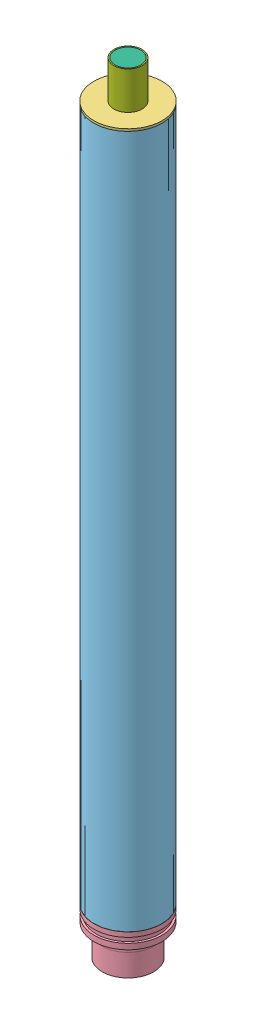
SolidWorks assembly N2850_Reload_Asm, configuration Default. Lengths in mm.
Overall size (129.5 1052.3 129.5).
16 component instances, 7 part files, 30 mates.
Components (placement in the parent):
- N2850P_Grain-1: N2850P_Grain [Default] at (67.2787 -348.6977 28.0701) size (85.47 152.4 85.47)
- N2850P_Grain-2: N2850P_Grain [Default] at (67.2787 -656.7997 28.0701) x (0.90713 0 0.42085) z (-0.42085 0 0.90713) size (85.47 152.4 85.47)
- N2850P_Grain-3: N2850P_Grain [Default] at (67.2787 -1117.3017 28.0701) x (0.920776 0 0.390092) z (-0.390092 0 0.920776) size (85.47 152.4 85.47)
- N2850P_Grain-4: N2850P_Grain [Default] at (67.2787 -809.1997 28.0701) x (0.999333 0 -0.03651) z (0.03651 0 0.999333) size (85.47 152.4 85.47)
- N2850P_Grain-5: N2850P_Grain [Default] at (67.2787 -502.7487 28.0701) x (-0.989532 0 0.144312) z (-0.144312 0 -0.989532) size (85.47 152.4 85.47)
- N2850P_Grain_O_Ring-1: N2850P_Grain_O_Ring [Default] at (67.2787 -503.5742 28.0701) x (0.875027 0 -0.484075) z (0.484075 0 0.875027) size (85.47 1.65 85.47)
- N2850P_Grain_O_Ring-2: N2850P_Grain_O_Ring [Default] at (67.2787 -657.6252 28.0701) x (0.935457 0 0.353441) z (-0.353441 0 0.935457) size (85.47 1.65 85.47)
- N2850P_Grain_O_Ring-3: N2850P_Grain_O_Ring [Default] at (67.2787 -349.5232 28.0701) x (0.895254 0 -0.445557) z (0.445557 0 0.895254) size (85.47 1.65 85.47)
- N2850P_Grain_O_Ring-4: N2850P_Grain_O_Ring [Default] at (67.2787 -964.0762 28.0701) size (85.47 1.65 85.47)
- N2850P_Grain_O_Ring-5: N2850P_Grain_O_Ring [Default] at (67.2787 -810.0252 28.0701) x (0.989289 0 -0.145969) z (0.145969 0 0.989289) size (85.47 1.65 85.47)
- N2850P_Grain-6: N2850P_Grain [Default] at (67.2787 -963.2507 28.0701) x (0.981998 0 0.188893) z (-0.188893 0 0.981998) size (85.47 152.4 85.47)
- N2850P_Forward_Seal_Disc-1: N2850P_Forward_Seal_Disc [Default] at (67.2787 -186.6203 28.0701) size (92.15 6.17 92.15)
- N2850P_Nozel-1: N2850P_Nozel [Default] at (67.2787 -1175.2142 28.0701) x (-1 0 0) z (0 0 1) size (91.69 70.82 91.69)
- N2850P_Reload_Liner-1: N2850P_Reload_Liner [Default] at (67.2787 -189.6429 28.0701) x (-0.742612 0 0.669722) z (0.669722 0 0.742612) size (91.69 936.62 91.69)
- N2850P_Smoke_Grain-1: N2850P_Smoke_Grain [Default] at (67.2787 -135.8711 28.0701) x (1 0 0) z (0 -1 0) size (34.8 34.8 50.75)
- N2850P_Smoke_Grain_Liner-1: N2850P_Smoke_Grain_Liner [Default] at (67.2787 -135.8203 28.0701) x (1 0 0) z (0 -1 0) size (38.1 38.1 50.8)
Mates (geometry in assembly coordinates):
- Coincident2: coincident aligned: axis of N2850P_Nozel-1 through (67.2787 -1188.1169 28.0701) axis (0 1 0); axis of N2850P_Reload_Liner-1 through (67.2787 -1126.2679 28.0701) axis (0 1 0)
- Coincident3: coincident anti-aligned: plane of N2850P_Nozel-1 through (110.2047 -1126.2679 28.0701) normal (0 1 0); plane of N2850P_Reload_Liner-1 through (67.2787 -1126.2679 28.0701) normal (0 -1 0)
- Coincident4: coincident aligned: axis of N2850P_Smoke_Grain-1 through (67.2787 -186.6203 28.0701) axis (0 1 0); axis of N2850P_Smoke_Grain_Liner-1 through (67.2787 -186.6203 28.0701) axis (0 1 0)
- Coincident5: coincident aligned: plane of N2850P_Smoke_Grain-1 through (67.2787 -186.6203 28.0701) normal (0 -1 0); plane of N2850P_Smoke_Grain_Liner-1 through (67.2787 -186.6203 28.0701) normal (0 -1 0)
- Coincident6: coincident anti-aligned: plane of N2850P_Forward_Seal_Disc-1 through (57.7537 -186.6203 28.0701) normal (0 1 0); plane of N2850P_Smoke_Grain-1 through (67.2787 -186.6203 28.0701) normal (0 -1 0)
- Coincident7: coincident aligned: axis of N2850P_Forward_Seal_Disc-1 through (67.2787 -192.7925 28.0701) axis (0 1 0); axis of N2850P_Smoke_Grain-1 through (67.2787 -186.6203 28.0701) axis (0 1 0)
- Coincident8: coincident aligned: axis of N2850P_Forward_Seal_Disc-1 through (67.2787 -192.7925 28.0701) axis (0 1 0); axis of N2850P_Reload_Liner-1 through (67.2787 -1126.2679 28.0701) axis (0 1 0)
- Coincident9: coincident aligned: axis of N2850P_Grain-4 through (67.2787 -656.7997 28.0701) axis (0 -1 0); axis of N2850P_Grain_O_Ring-2 through (67.2787 -633.4481 28.0701) axis (0 -1 0)
- Coincident10: coincident aligned: axis of N2850P_Grain-2 through (67.2787 -504.3997 28.0701) axis (0 -1 0); axis of N2850P_Grain_O_Ring-1 through (67.2787 -479.3971 28.0701) axis (0 -1 0)
- Coincident11: coincident aligned: axis of N2850P_Grain-5 through (67.2787 -350.3487 28.0701) axis (0 -1 0); axis of N2850P_Grain_O_Ring-3 through (67.2787 -325.3461 28.0701) axis (0 -1 0)
- Tangent4: tangent: plane of N2850P_Grain-5 through (67.2787 -350.3487 28.0701) normal (0 1 0); face of N2850P_Grain_O_Ring-3
- Coincident12: coincident aligned: axis of N2850P_Grain-3 through (67.2787 -964.9017 28.0701) axis (0 -1 0); axis of N2850P_Grain_O_Ring-4 through (67.2787 -939.8991 28.0701) axis (0 -1 0)
- Coincident13: coincident aligned: axis of N2850P_Grain_O_Ring-5 through (67.2787 -785.8481 28.0701) axis (0 -1 0); axis of N2850P_Grain-6 through (67.2787 -810.8507 28.0701) axis (0 -1 0)
- Tangent6: tangent: face of N2850P_Grain_O_Ring-5; plane of N2850P_Grain-6 through (67.2787 -810.8507 28.0701) normal (0 1 0)
- Coincident14: coincident aligned: axis of N2850P_Grain-2 through (67.2787 -504.3997 28.0701) axis (0 -1 0); axis of N2850P_Grain-4 through (67.2787 -656.7997 28.0701) axis (0 -1 0)
- Tangent7: tangent: plane of N2850P_Grain-2 through (67.2787 -656.7997 28.0701) normal (0 -1 0); face of N2850P_Grain_O_Ring-2
- Coincident15: coincident aligned: axis of N2850P_Grain-5 through (67.2787 -350.3487 28.0701) axis (0 -1 0); axis of N2850P_Grain_O_Ring-1 through (67.2787 -479.3971 28.0701) axis (0 -1 0)
- Coincident17: coincident aligned: axis of N2850P_Grain-1 through (67.2787 -196.2977 28.0701) axis (0 -1 0); axis of N2850P_Grain-5 through (67.2787 -350.3487 28.0701) axis (0 -1 0)
- Tangent9: tangent: plane of N2850P_Grain-1 through (67.2787 -348.6977 28.0701) normal (0 -1 0); face of N2850P_Grain_O_Ring-3
- Coincident20: coincident aligned: axis of N2850P_Grain-4 through (67.2787 -656.7997 28.0701) axis (0 -1 0); axis of N2850P_Grain_O_Ring-5 through (67.2787 -785.8481 28.0701) axis (0 -1 0)
- Tangent11: tangent: plane of N2850P_Grain-4 through (67.2787 -809.1997 28.0701) normal (0 -1 0); face of N2850P_Grain_O_Ring-5
- Coincident22: coincident aligned: axis of N2850P_Grain_O_Ring-4 through (67.2787 -939.8991 28.0701) axis (0 -1 0); axis of N2850P_Grain-6 through (67.2787 -810.8507 28.0701) axis (0 -1 0)
- Tangent12: tangent: plane of N2850P_Grain-3 through (67.2787 -964.9017 28.0701) normal (0 1 0); face of N2850P_Grain_O_Ring-4
- Tangent13: tangent: face of N2850P_Grain_O_Ring-4; plane of N2850P_Grain-6 through (67.2787 -963.2507 28.0701) normal (0 -1 0)
- Tangent14: tangent: plane of N2850P_Grain-4 through (67.2787 -656.7997 28.0701) normal (0 1 0); face of N2850P_Grain_O_Ring-2
- Tangent15: tangent: face of N2850P_Grain_O_Ring-1; plane of N2850P_Grain-2 through (67.2787 -504.3997 28.0701) normal (0 1 0)
- Tangent16: tangent: plane of N2850P_Grain-5 through (67.2787 -502.7487 28.0701) normal (0 -1 0); face of N2850P_Grain_O_Ring-1
- Coincident24: coincident anti-aligned: axis of N2850P_Reload_Liner-1 through (67.2787 -1126.2679 28.0701) axis (0 1 0); axis of N2850P_Grain-3 through (67.2787 -964.9017 28.0701) axis (0 -1 0)
- Coincident25: coincident anti-aligned: plane of N2850P_Nozel-1 through (107.7917 -1117.3017 28.0701) normal (0 1 0); plane of N2850P_Grain-3 through (67.2787 -1117.3017 28.0701) normal (0 -1 0)
- Coincident26: coincident aligned: plane of N2850P_Forward_Seal_Disc-1 through (21.2031 -189.6429 28.0701) normal (0 -1 0); circle of N2850P_Reload_Liner-1
